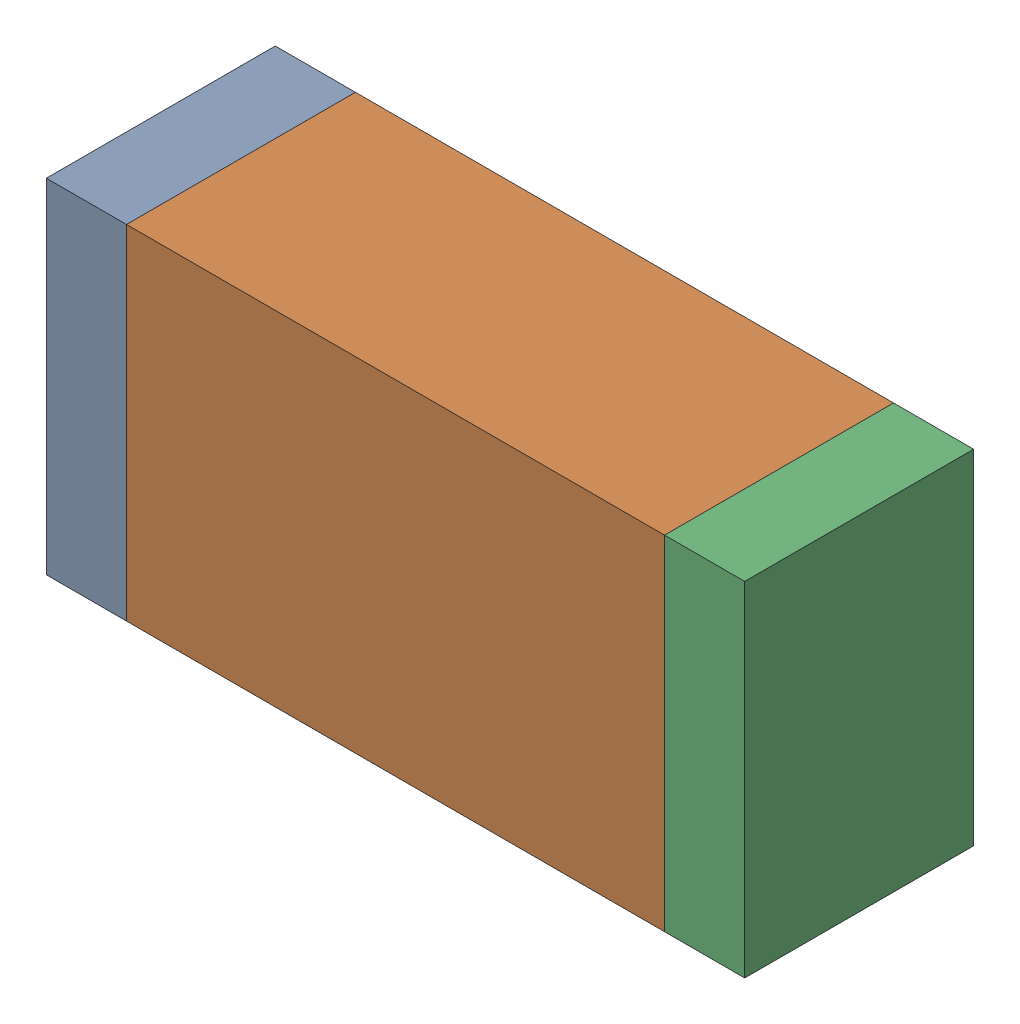
SolidWorks assembly R11, configuration Default. Lengths in mm.
Overall size (1.55 0.76 0.51).
6 component instances, 2 part files, 0 mates.
Components (placement in the parent):
- 822490216-1: 822490216 [Default] at (43.6114 19.5833 0) size (0.18 0.76 0.51)
  - Extruded-1: Extruded [Default] at origin size (0.18 0.76 0.51)
- 822498920-1: 822498920 [Default] at (44.2972 19.5833 0) size (1.19 0.76 0.51)
  - Extruded_2-1: Extruded_2 [Default] at origin size (1.19 0.76 0.51)
- 822490216-2: 822490216 [Default] at (44.983 19.5833 0) size (0.18 0.76 0.51)
  - Extruded-1: Extruded [Default] at origin size (0.18 0.76 0.51)
